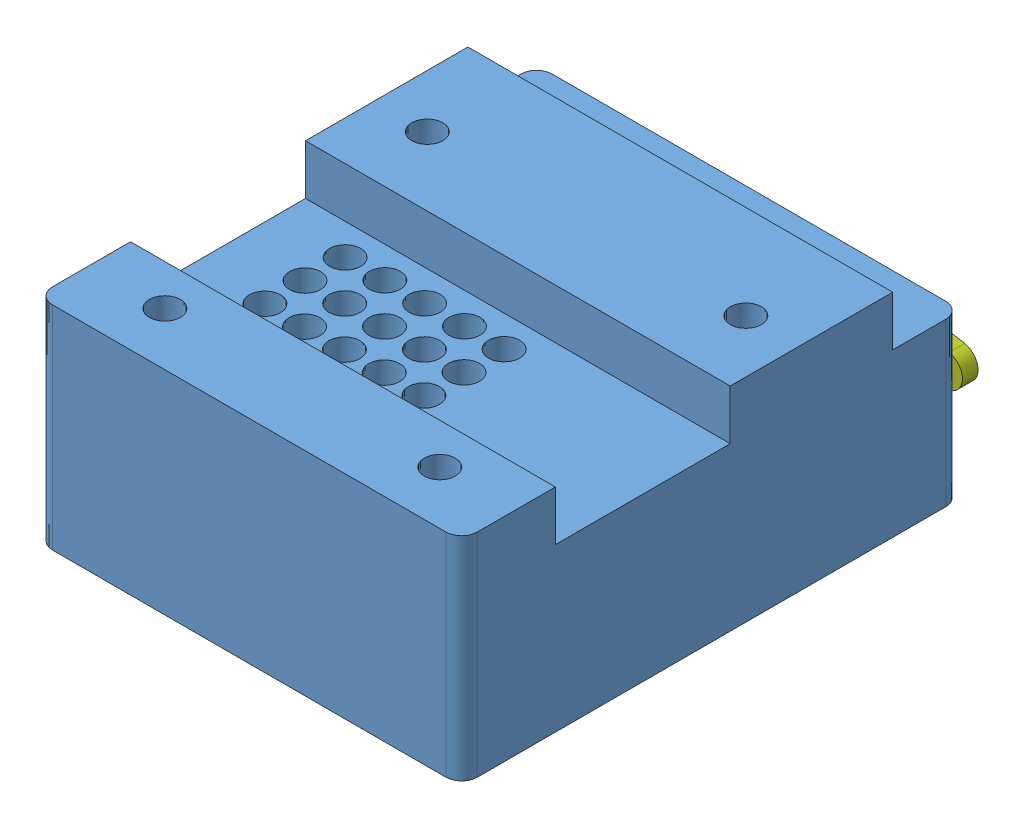
SolidWorks assembly Hop DK, configuration Default. Lengths in mm.
Overall size (68.39 34 87.55).
7 component instances, 7 part files, 16 mates.
Components (placement in the parent):
- hop-1: hop [Default] at (-6.6374 48.974 17.1715) size (68 34 80)
- TOWER PRO MG-995, ANALOG SERVO, BODY, TOP-2: TOWER PRO MG-995, ANALOG SERVO, BODY, TOP [Default] at (27.3626 39.074 28.1715) x (0 1 0) z (-1 0 0) size (19.8 13.2 54.6)
- TOWER PRO MG-995, ANALOG SERVO, BODY, MIDDLE-1: TOWER PRO MG-995, ANALOG SERVO, BODY, MIDDLE [Default] at (27.3626 39.074 38.4215) x (0 -1 0) z (-1 0 0) size (19.8 20.5 40.6)
- TOWER PRO MG-995, ANALOG SERVO, BODY, BOTTOM-1: TOWER PRO MG-995, ANALOG SERVO, BODY, BOTTOM [Default] at (27.3626 39.074 55.0715) x (0 -1 0) z (1 0 0) size (19.8 6.4 40.6)
- +++ ESP8266 NodeMCU Board +++.stp-1: +++ ESP8266 NodeMCU Board +++.stp [Default] at (17.4376 33.974 72.0165) x (0 0 -1) z (-1 0 0) size (25.69 12.59 48.54)
- TOWER PRO MG-995, ANALOG SERVO, SHAFT-2: TOWER PRO MG-995, ANALOG SERVO, SHAFT [Default] at (37.6626 39.074 28.4715) x (-0.093447 -0.995624 0) z (0.995624 -0.093447 0) size (5.76 17.5 5.8)
- TOWER PRO MG-995, ANALOG SERVO, HORN-1: TOWER PRO MG-995, ANALOG SERVO, HORN [Default] at (37.6626 39.074 15.3715) x (-0.014039 -0.999901 0) z (0.999901 -0.014039 0) size (12.7 5.75 38.36)
Mates (geometry in assembly coordinates):
- Coincident1: coincident: plane of TOWER PRO MG-995, ANALOG SERVO, BODY, TOP-2 through (27.3626 39.074 28.1715) normal (0 0 1); plane of TOWER PRO MG-995, ANALOG SERVO, BODY, MIDDLE-1 through (27.3626 39.074 28.1715) normal (0 0 -1)
- Coincident2: coincident: plane of TOWER PRO MG-995, ANALOG SERVO, BODY, TOP-2 through (47.6626 29.174 19.1715) normal (0 -1 0); plane of TOWER PRO MG-995, ANALOG SERVO, BODY, MIDDLE-1 through (47.6626 29.174 48.6715) normal (0 -1 0)
- Concentric1: concentric: cylinder of TOWER PRO MG-995, ANALOG SERVO, BODY, TOP-2 through (46.6626 47.974 19.1715) axis (0 0 1) radius 1; cylinder of TOWER PRO MG-995, ANALOG SERVO, BODY, MIDDLE-1 through (46.6626 47.974 48.6715) axis (0 0 -1) radius 1
- Coincident3: coincident: plane of hop-1 through (-6.6374 48.974 17.1715) normal (0 -1 0); plane of TOWER PRO MG-995, ANALOG SERVO, BODY, MIDDLE-1 through (47.6626 48.974 48.6715) normal (0 1 0)
- Coincident4: coincident: plane of hop-1 through (-6.6374 26.974 28.1715) normal (0 0 -1); plane of TOWER PRO MG-995, ANALOG SERVO, BODY, TOP-2 through (27.3626 39.074 28.1715) normal (0 0 1)
- Distance1: distance = 0.2 mm: plane of hop-1 through (6.8626 26.974 17.1715) normal (1 0 0); plane of TOWER PRO MG-995, ANALOG SERVO, BODY, MIDDLE-1 through (7.0626 48.974 48.6715) normal (-1 0 0)
- Coincident5: coincident: plane of TOWER PRO MG-995, ANALOG SERVO, BODY, MIDDLE-1 through (27.3626 39.074 48.6715) normal (0 0 1); plane of TOWER PRO MG-995, ANALOG SERVO, BODY, BOTTOM-1 through (27.3626 39.074 48.6715) normal (0 0 -1)
- Concentric2: concentric: cylinder of TOWER PRO MG-995, ANALOG SERVO, BODY, MIDDLE-1 through (46.6626 30.174 48.6715) axis (0 0 -1) radius 1; cylinder of TOWER PRO MG-995, ANALOG SERVO, BODY, BOTTOM-1 through (46.6626 30.174 48.6715) axis (0 0 1) radius 1
- Coincident6: coincident: plane of hop-1 through (-6.6374 33.974 17.1715) normal (0 -1 0); plane of +++ ESP8266 NodeMCU Board +++.stp-1 through (17.4376 33.974 72.0165) normal (0 1 0)
- Coincident7: coincident: plane of hop-1 through (-6.6374 33.974 17.1715) normal (0 -1 0); plane of +++ ESP8266 NodeMCU Board +++.stp-1 through (17.4376 33.974 72.0165) normal (0 1 0)
- Coincident8: coincident: plane of hop-1 through (-6.6374 52.974 17.1715) normal (-1 0 0); plane of +++ ESP8266 NodeMCU Board +++.stp-1 through (-6.6374 33.974 82.8615) normal (-1 0 0)
- Coincident9: coincident: plane of hop-1 through (-6.6374 33.974 84.8615) normal (0 0 1); plane of +++ ESP8266 NodeMCU Board +++.stp-1 through (39.5126 33.974 84.8615) normal (0 0 1)
- Concentric4: concentric: cylinder of TOWER PRO MG-995, ANALOG SERVO, BODY, TOP-2 through (37.6626 39.074 28.1715) axis (0 0 -1) radius 3; cylinder of TOWER PRO MG-995, ANALOG SERVO, SHAFT-2 through (37.6626 39.074 14.9715) axis (0 0 -1) radius 2.65
- Distance5: distance = 4 mm: plane of TOWER PRO MG-995, ANALOG SERVO, BODY, TOP-2 through (37.6626 39.074 14.9715) normal (0 0 -1); plane of TOWER PRO MG-995, ANALOG SERVO, SHAFT-2 through (37.6626 39.074 10.9715) normal (0 0 -1)
- Concentric6: concentric: cylinder of TOWER PRO MG-995, ANALOG SERVO, SHAFT-2 through (37.6626 39.074 14.9715) axis (0 0 -1) radius 0.8; cylinder of TOWER PRO MG-995, ANALOG SERVO, HORN-1 through (37.6626 39.074 15.3715) axis (0 0 -1) radius 1.4
- Coincident17: coincident: plane of TOWER PRO MG-995, ANALOG SERVO, SHAFT-2 through (37.6626 39.074 10.9715) normal (0 0 -1); plane of TOWER PRO MG-995, ANALOG SERVO, HORN-1 through (37.6626 39.074 10.9715) normal (0 0 -1)
